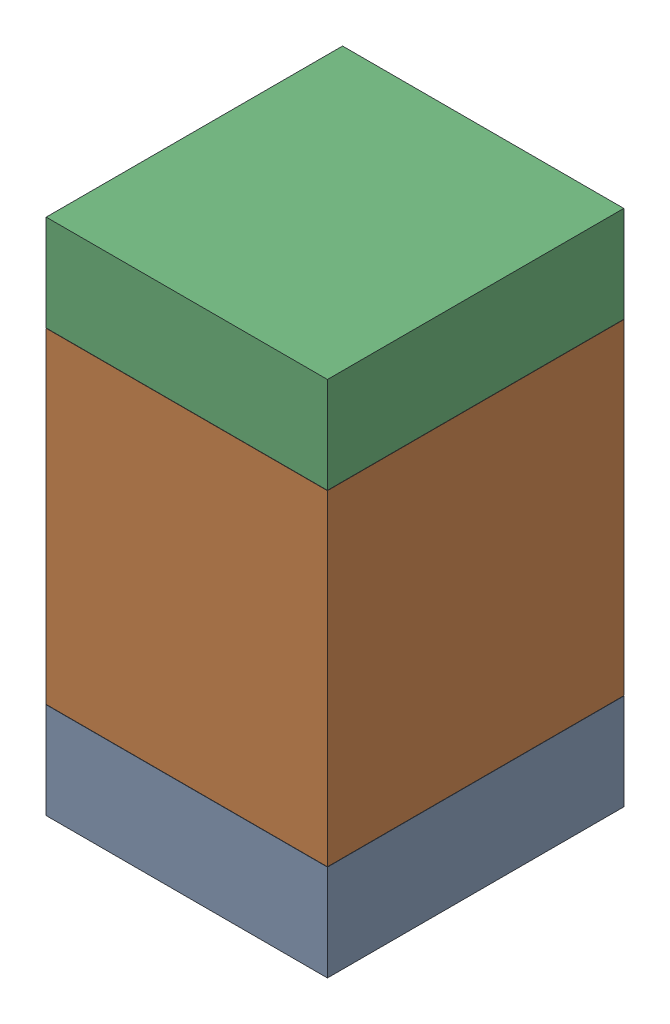
SolidWorks assembly R1, configuration Default. Lengths in mm.
Overall size (0.95 1.75 1).
6 component instances, 2 part files, 0 mates.
Components (placement in the parent):
- 6575495072-1: 6575495072 [Default] at (15.24 18.2105 0) size (0.95 0.32 1)
  - Extruded_6-1: Extruded_6 [Default] at origin size (0.95 0.32 1)
- 6575494912-1: 6575494912 [Default] at (15.24 18.923 0) size (0.95 1.1 1)
  - Extruded_7-1: Extruded_7 [Default] at origin size (0.95 1.1 1)
- 6575495072-2: 6575495072 [Default] at (15.24 19.6355 0) size (0.95 0.32 1)
  - Extruded_6-1: Extruded_6 [Default] at origin size (0.95 0.32 1)
